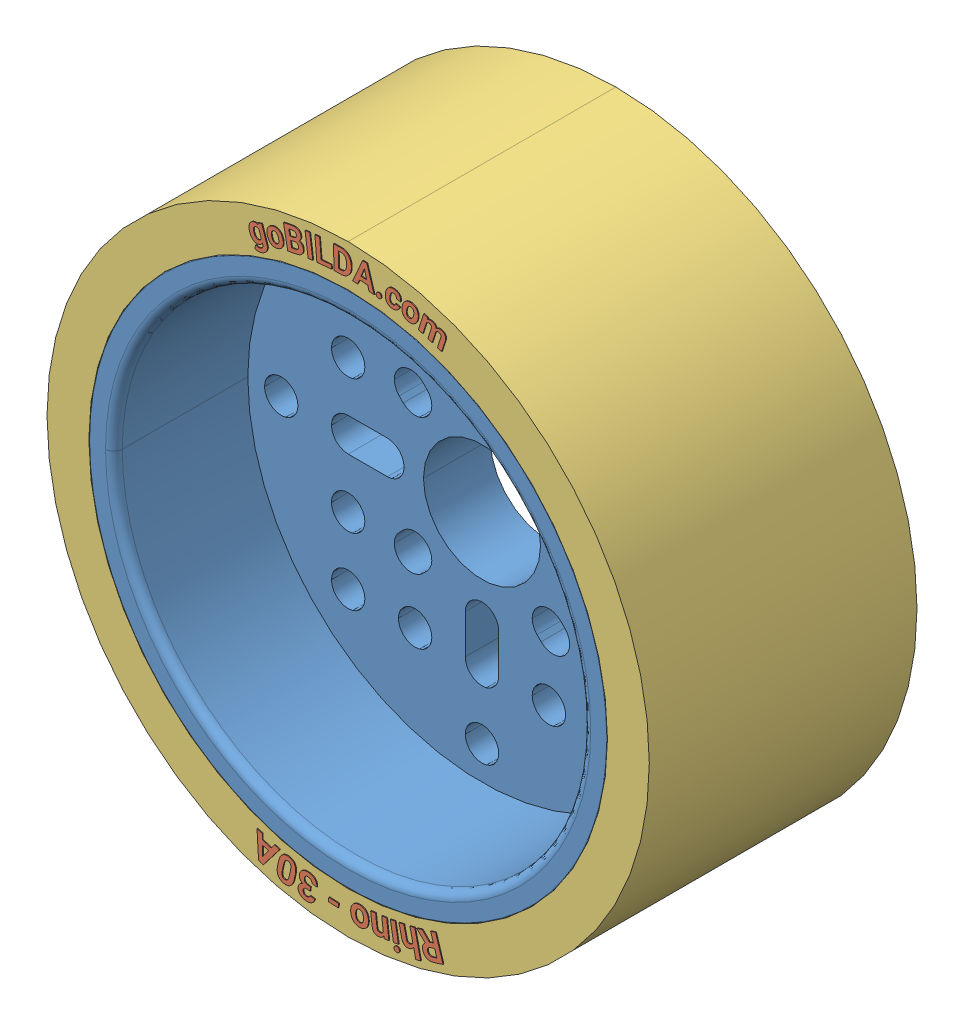
SolidWorks assembly 72mm Rhino Wheel 3614-0014-0072, configuration Default. Lengths in mm.
Overall size (72 72 32.2).
4 component instances, 3 part files, 0 mates.
Components (placement in the parent):
- 3614-0014-0072 wheel.STEP-1: 3614-0014-0072 wheel.STEP [Default] at (-66.6535 18.423 6.6559) size (62 62 32)
- 3614-0014-0072 Text.STEP-1: 3614-0014-0072 Text.STEP [Default] at (-102.6535 54.423 38.6559) size (23.56 69.71 0.1)
- 3614-0014-0072 wheel ring.STEP-1: 3614-0014-0072 wheel ring.STEP [Default] at (-66.6535 18.423 38.6559) x (1 0 0) z (0 1 0) size (72 32 72)
- 3614-0014-0072 Text.STEP-2: 3614-0014-0072 Text.STEP [Default] at (-102.4797 -17.7501 6.6559) x (0.999988 0.004818 0) z (0 0 -1) size (23.56 69.71 0.1)
